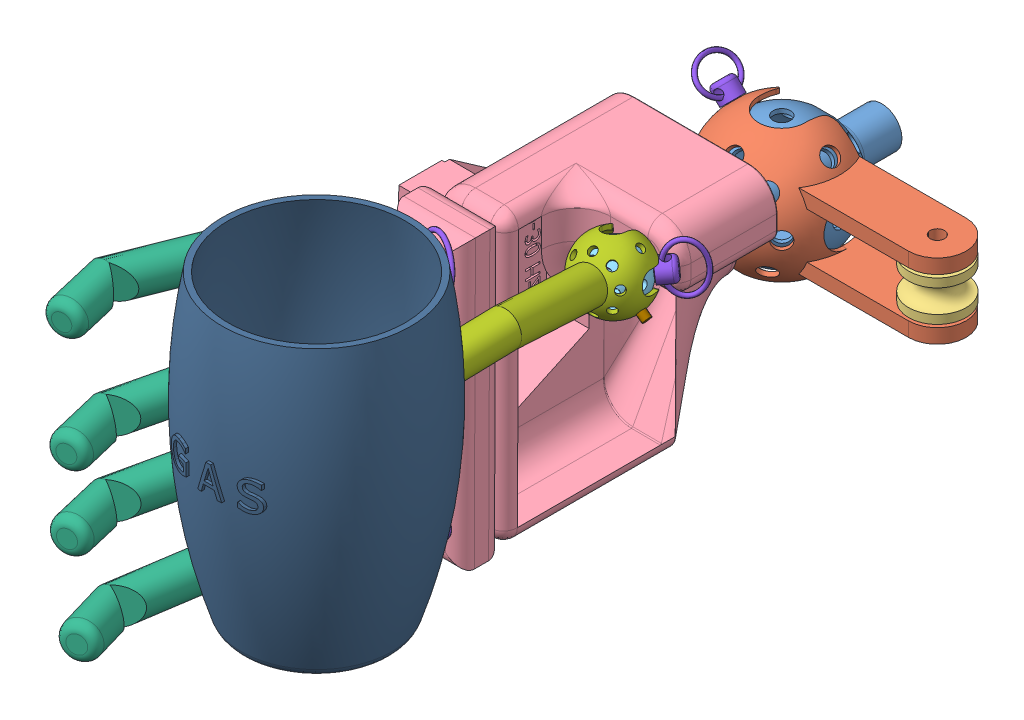
SolidWorks assembly рука, configuration По умолчанию. Lengths in mm.
Overall size (170.43 189.97 295.05).
26 component instances, 10 part files, 0 mates.
Components (placement in the parent):
- Wrist (Ball)-1: Wrist (Ball) [По умолчанию] at (130.9432 19.5819 -34.9204) x (1 0 0) z (0 1 0) size (42 55.8 41.57)
- Wrist (Socket)-1: Wrist (Socket) [По умолчанию] at (130.9432 19.5819 -34.9204) x (1 0 0) z (0 -1 0) size (89.1 37 45.25)
- Wrist (Pulley)-1: Wrist (Pulley) [По умолчанию] at (186.0432 19.5819 -33.9204) x (-0.070211 0 -0.997532) z (0 1 0) size (20 20 14)
- Finger (Hand)-2-1: Finger (Hand)-2 [По умолчанию] at (156.7967 12.6253 74.3496) x (0.004145 0.999991 0) z (0 0 1) size (100.4 77.16 97.92)
- Finger (Ball)-1: Finger (Ball) [По умолчанию] at (131.109 59.5815 99.3496) x (0.811963 0.583709 0) z (-0.583709 0.811963 0) size (20 22.54 19.77)
- Finger (Socket)-1: Finger (Socket) [По умолчанию] at (131.0283 59.0881 99.3496) x (-0.580287 -0.621598 -0.526197) z (-0.352032 0.774074 -0.526197) size (38.39 91.08 37.87)
- Finger (Ball)-2: Finger (Ball) [По умолчанию] at (130.995 32.0818 99.3496) x (-0.772654 0.634827 0) z (-0.634827 -0.772654 0) size (20 22.54 19.77)
- Finger (Socket)-2: Finger (Socket) [По умолчанию] at (131.0437 31.5842 99.3496) x (-0.4251 -0.752117 -0.503598) z (-0.562927 0.655364 -0.503598) size (38.39 91.08 37.87)
- Finger (Ball)-3: Finger (Ball) [По умолчанию] at (130.8913 7.082 99.3496) x (-0.135652 0.990757 0) z (-0.990757 -0.135652 0) size (20 22.54 19.77)
- Finger (Socket)-3: Finger (Socket) [По умолчанию] at (130.8235 7.5774 99.3496) x (-0.398953 -0.768327 -0.500509) z (-0.590794 0.632814 -0.500509) size (38.39 91.08 37.87)
- Finger (Ball)-4: Finger (Ball) [По умолчанию] at (130.7773 -20.4178 99.3496) x (-0.176458 0.984308 0) z (-0.984308 -0.176458 0) size (20 22.54 19.77)
- Finger (Socket)-4: Finger (Socket) [По умолчанию] at (130.6891 -19.9256 99.3496) x (-0.399706 -0.790035 -0.464844) z (-0.649255 0.601987 -0.464844) size (38.39 91.08 37.87)
- Finger (Ball)-5: Finger (Ball) [По умолчанию] at (168.6086 59.4261 60.889) x (-0.15201 0.988379 0) z (-0.988379 -0.15201 0) size (20 22.54 19.77)
- Thumb (Socket)-1: Thumb (Socket) [По умолчанию] at (168.2055 59.7218 60.889) x (-0.161961 0.97481 -0.153344) z (0.978427 0.13844 -0.153344) size (24.44 80.4 23.92)
- Wrist (Lock Pin)-1: Wrist (Lock Pin) [По умолчанию] at (130.8237 59.9784 99.9185) x (0.544202 -0.757007 0.361641) z (0.811963 0.583709 0) size (19.35 7.53 29.68)
- Wrist (Lock Pin)-2: Wrist (Lock Pin) [По умолчанию] at (131.0293 32.0535 100.0983) x (0.711911 -0.584919 -0.388656) z (0.634827 0.772654 0) size (19.35 7.53 29.68)
- Wrist (Lock Pin)-3: Wrist (Lock Pin) [По умолчанию] at (130.3129 7.5211 99.5369) x (0.444577 -0.337498 0.829727) z (0.60465 0.796491 0) size (19.35 7.53 29.68)
- Wrist (Lock Pin)-4: Wrist (Lock Pin) [По умолчанию] at (130.6144 -20.3044 100.0729) x (0.818663 -0.56976 -0.071862) z (0.571237 0.820785 0) size (19.35 7.53 29.68)
- Wrist (Lock Pin)-5: Wrist (Lock Pin) [По умолчанию] at (168.115 59.2086 60.368) x (-0.044313 0.993251 0.107186) z (0.69889 0.107487 -0.707107) size (19.35 7.53 29.68)
- Finger (Pivot Pin, Short)-1: Finger (Pivot Pin, Short) [По умолчанию] at (131.0283 59.0881 99.3496) x (-0.982653 0.160707 0.092552) z (0.1614 0.986889 0) size (4 4 26)
- Finger (Pivot Pin, Short)-2: Finger (Pivot Pin, Short) [По умолчанию] at (131.0437 31.5842 99.3496) x (-0.501883 -0.049147 0.863538) z (-0.097459 0.99524 0) size (4 4 26)
- Finger (Pivot Pin, Short)-3: Finger (Pivot Pin, Short) [По умолчанию] at (130.8235 7.5774 99.3496) x (0.969812 0.132784 0.204533) z (0.135652 -0.990757 0) size (4 4 26)
- Finger (Pivot Pin, Short)-4: Finger (Pivot Pin, Short) [По умолчанию] at (130.6891 -19.9256 99.3496) x (0.982199 0.176079 -0.06543) z (0.176458 -0.984308 0) size (4 4 26)
- Finger (Pivot Pin, Short)-5: Finger (Pivot Pin, Short) [По умолчанию] at (170.2214 58.2433 60.889) x (-0.342638 -0.467186 -0.815069) z (-0.806376 0.591403 0) size (4 4 26)
- Wrist (Lock Pin)-6: Wrist (Lock Pin) [По умолчанию] at (121.5719 30.0096 -34.8536) x (-0.17537 -0.17537 -0.968757) z (-0.707107 0.707107 0) size (19.35 7.53 29.68)
- Стакан1-1: Стакан1 [По умолчанию] at (191.5137 30.0598 187.4764) size (72.92 104.75 74.31)
